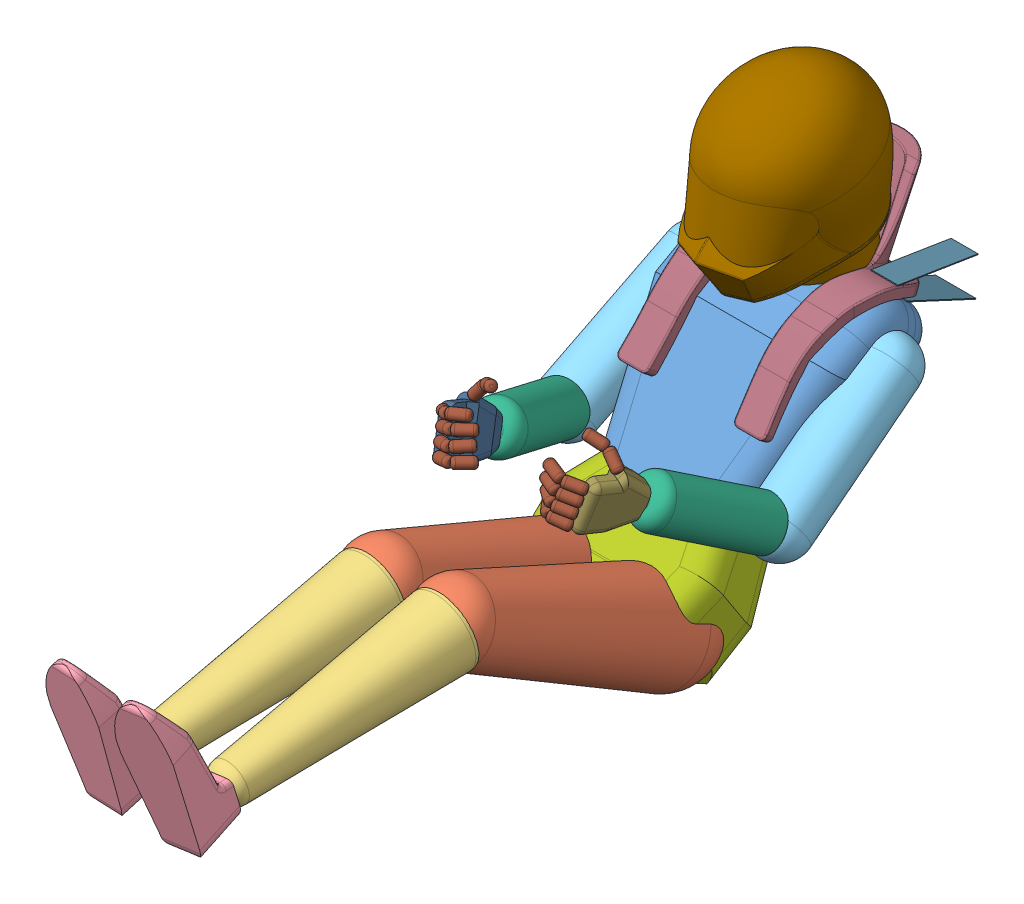
SolidWorks assembly Driver, configuration Default. Lengths in mm.
Overall size (561.73 872.52 1538.68).
40 component instances, 14 part files, 28 mates.
Components (placement in the parent):
- Torso-1: Torso [Default] at (0 0 109.134) x (1 0 0) z (0 0.615661 0.788011) size (365.73 385.32 193.18)
- Upper Leg-1: Upper Leg [Default] at (-76.2 -88.1498 244.8728) x (-0.031181 -0.895731 0.443502) z (0.999512 -0.028692 0.012323) size (181.92 574.72 181.92)
- Lower Leg-1: Lower Leg [Default] at (-75.5001 95.9894 616.8233) x (-0.026742 -0.990268 -0.136579) z (0.999512 -0.028692 0.012323) size (141.98 445.01 146.74)
- Foot-1: Foot [Default] at (-26.031 33.7607 1058.3254) x (-0.999512 0.028692 -0.012323) z (-0.023689 -0.953831 -0.299409) size (130.33 89.92 298.96)
- Upper Arm-1: Upper Arm [Default] at (-203.2 82.3059 139.7838) x (-0.734501 -0.529681 -0.424201) z (0.673249 -0.647184 -0.357615) size (101.6 397.72 101.6)
- Lower Arm-1: Lower Arm [Default] at (-131.2084 188.4007 359.0486) x (-0.836432 0.547989 0.009474) z (-0.283431 -0.417696 -0.863248) size (88.98 88.98 254)
- Upper Leg-2: Upper Leg [Default] at (76.2 -88.1498 244.8728) x (0.999378 0.012809 0.032851) z (0.003362 0.892829 -0.450382) size (181.92 574.72 181.92)
- Lower Leg-2: Lower Leg [Default] at (61.6326 98.7046 615.1809) x (0.999378 0.012809 0.032851) z (-0.017528 0.988884 0.14765) size (141.98 445.01 146.74)
- Upper Arm-3: Upper Arm [Default] at (203.2 90.5447 144.9989) x (0.550591 -0.68786 -0.472968) z (0.830425 0.509095 0.226312) size (101.6 397.72 101.6)
- Lower Arm-2: Lower Arm [Default] at (153.5956 217.6679 359.2302) x (0.197734 0.862423 -0.465971) z (0.195293 -0.500485 -0.843431) size (88.98 88.98 254)
- ass 2-1: ass 2 [Default] at (0 -125.267 302.0282) x (1 0 0) z (0 0.544639 -0.838671) size (327.93 194.64 237.23)
- neck-1: neck [Default] at (0 318.5276 -109.0294) x (1 0 0) z (0 -0.034899 0.999391) size (139.7 241.3 139.7)
- head_helmet-1: head_helmet [Default] at (-0.0708 394.2262 -107.0569) x (0.003968 0.252405 -0.967614) z (0.99999 -0.002944 0.003333) size (346.14 436.25 253.56)
- right_hand-1: right_hand [FU!] at (-108.5097 191.8432 354.8281) x (0.207721 -0.90009 0.383001) z (-0.10626 -0.409987 -0.90588) size (132.83 85.64 143.76)
  - right_palm-1: right_palm [Default] at origin size (98.25 47.38 101.6)
  - finger-1: finger [Default] at (-49.3039 24.13 -53.0317) x (0.50335 -0.086462 -0.859746) z (-0.59338 0.688689 -0.416662) size (19.05 38.1 19.05)
  - finger-2: finger [Default] at (-77.8162 -30.2072 -90.8643) x (0.987884 -0.154582 -0.013755) z (-0.098127 -0.690838 0.71632) size (19.05 38.1 19.05)
  - finger-3: finger [Default] at (9.7976 35.56 -101.6) x (0.49206 -0.497036 0.714726) z (0.870545 0.285971 -0.400465) size (19.05 38.1 19.05)
  - finger-4: finger [Default] at (-11.0552 35.56 -101.6) x (-0.596996 -0.425876 0.679872) z (0.798657 -0.395556 0.453522) size (19.05 38.1 19.05)
  - finger-5: finger [Default] at (10.0013 4.3464 -123.4468) x (0.772648 0.223249 0.594285) z (0.608545 -0.527064 -0.593192) size (19.05 38.1 19.05)
  - finger-6: finger [Default] at (-32.7293 35.56 -101.6) x (0.463457 -0.70203 0.540704) z (0.882821 0.313208 -0.35004) size (19.05 38.1 19.05)
  - finger-7: finger [Default] at (-13.9425 4.5567 -123.5561) x (0.286297 -0.469016 -0.835498) z (-0.951062 -0.033307 -0.3072) size (19.05 38.1 19.05)
  - finger-8: finger [Default] at (31.3089 1.786 -119.2312) x (-0.232922 0.635074 0.736497) z (0.966447 0.066829 0.24802) size (19.05 38.1 19.05)
  - finger-9: finger [Default] at (-35.6395 11.1922 -130.7437) x (0.620311 -0.242152 -0.746041) z (-0.779676 -0.08662 -0.620163) size (19.05 38.1 19.05)
  - finger-10: finger [Default] at (31.0529 35.56 -101.6) x (0.609441 -0.363266 0.704713) z (0.792803 0.28676 -0.537803) size (19.05 38.1 19.05)
- left_hand-1: left_hand [FU!] at (131.8172 221.7495 351.886) x (0.247782 0.946 -0.209018) z (0.261085 -0.272965 -0.925918) size (130.8 89.44 144.04)
  - left_palm-1: left_palm [Default] at origin size (101.6 47.38 101.6)
  - finger-1: finger [Default] at (50.8 26.2111 -54.3719) x (0.69442 0.499709 -0.517757) z (-0.549549 -0.096197 -0.829905) size (19.05 38.1 19.05)
  - finger-2: finger [Default] at (73.4963 -34.5954 -87.6301) x (0.990971 0.115985 0.067264) z (0.027695 -0.667924 0.743714) size (19.05 38.1 19.05)
  - finger-3: finger [Default] at (9.7976 35.56 -101.6) x (0.363062 -0.686021 0.630524) z (0.928864 0.213116 -0.302975) size (19.05 38.1 19.05)
  - finger-4: finger [Default] at (-11.0552 35.56 -101.6) x (-0.291301 -0.669979 0.682841) z (0.953506 -0.261003 0.15068) size (19.05 38.1 19.05)
  - finger-5: finger [Default] at (6.9983 9.055 -128.826) x (0.521272 0.003675 0.853382) z (0.853132 -0.026867 -0.521003) size (19.05 38.1 19.05)
  - finger-6: finger [Default] at (-32.7293 35.56 -101.6) x (0.48185 -0.604968 0.633904) z (0.875847 0.310461 -0.369468) size (19.05 38.1 19.05)
  - finger-7: finger [Default] at (-13.9992 9.081 -128.8361) x (0.138413 -0.293729 -0.945814) z (-0.989877 -0.010765 -0.141518) size (19.05 38.1 19.05)
  - finger-8: finger [Default] at (28.0727 8.9831 -128.7366) x (0.183963 -0.101218 0.977708) z (0.981439 0.073735 -0.177031) size (19.05 38.1 19.05)
  - finger-9: finger [Default] at (-33.7471 7.6239 -127.4872) x (0.645236 0.399892 0.650967) z (0.763899 -0.350359 -0.541947) size (19.05 38.1 19.05)
  - finger-10: finger [Default] at (31.0529 35.56 -101.6) x (0.602627 -0.60222 0.523615) z (0.79418 0.388262 -0.467472) size (19.05 38.1 19.05)
- Foot-3: Foot [Default] at (104.3529 35.9422 1049.7777) x (-0.994071 -0.055729 0.093362) z (0.025364 -0.953827 -0.299285) size (130.33 89.92 298.96)
- HANS_Device-1: HANS_Device [Default] at origin size (315.01 260.03 405.05)
- SeatBelts-1: SeatBelts [Default] at origin size (323.29 466.97 646.34)
Mates (geometry in assembly coordinates):
- Coincident4: coincident: point of Upper Leg-1; point of Lower Leg-1
- Coincident5: coincident: point of Lower Leg-1; point of Foot-1
- Parallel1: parallel: plane of ?; unknown of ?
- Parallel2: parallel: plane of assembly; plane of assembly; plane of Upper Leg-1 through (-76.2 -88.1498 244.8728) normal (0.999512 -0.028692 0.012323); plane of Lower Leg-1 through (-75.5001 95.9894 616.8233) normal (0.999512 -0.028692 0.012323)
- Parallel3: parallel: plane of assembly; plane of assembly; plane of Lower Leg-1 through (-75.5001 95.9894 616.8233) normal (0.999512 -0.028692 0.012323); plane of Foot-1 through (-26.031 33.7607 1058.3254) normal (-0.999512 0.028692 -0.012323)
- Coincident9: coincident: point of Upper Arm-1; point of Lower Arm-1
- Parallel4: parallel: unknown of ?; unknown of ?
- Coincident11: coincident: point of Upper Leg-2; point of Lower Leg-2
- Parallel5: parallel: plane of assembly; plane of assembly; plane of Upper Leg-2 through (76.2 -88.1498 244.8728) normal (0.999378 0.012809 0.032851); plane of Lower Leg-2 through (61.6326 98.7046 615.1809) normal (0.999378 0.012809 0.032851)
- Coincident15: coincident: point of Upper Arm-3; point of Lower Arm-2
- Coincident16: coincident: point of Torso-1; point of Upper Arm-1
- Coincident17: coincident: point of Torso-1; point of Upper Arm-3
- Coincident18: coincident: point of Torso-1; point of ass 2-1
- Angle1: planar angle = 2.80998 rad: plane of assembly; plane of assembly; plane of Torso-1 through (0 0 109.134) normal (0 0.615661 0.788011); plane of ass 2-1 through (0 -125.267 302.0282) normal (0 -0.838671 -0.544639)
- Coincident21: coincident: point of Upper Leg-1; point of ass 2-1
- Coincident22: coincident: point of Upper Leg-2; point of ass 2-1
- Coincident25: coincident: plane of assembly; plane of assembly; plane of Torso-1 through (0 0 109.134) normal (1 0 0); plane of neck-1 through (0 318.5276 -109.0294) normal (1 0 0)
- Neck Angle: planar angle = 3.839724 rad: plane of assembly; plane of assembly; plane of Torso-1 through (0 0 109.134) normal (0 0.615661 0.788011); plane of neck-1 through (0 318.5276 -109.0294) normal (0 -0.034899 0.999391)
- Coincident27: coincident: point of Lower Arm-1; point of right_hand-1/right_palm-1
- Coincident28: coincident: line of assembly; line of Torso-1 through (201.5357 0 109.134) axis (-1 0 0); plane of assembly
- LEAN BACK ANGLE: planar angle = 3.804818 rad: plane of assembly through (0 0 0) normal (0 0 1); plane of Torso-1 through (0 0 109.134) normal (0 0.615661 0.788011); plane of assembly
- Coincident30: coincident: plane of assembly through (0 0 0) normal (1 0 0); plane of Torso-1 through (0 0 109.134) normal (1 0 0); plane of assembly
- Coincident31: coincident: point of Lower Arm-1; plane of assembly
- Coincident32: coincident: point of Lower Arm-2; plane of assembly
- Coincident33: coincident: point of Torso-1; point of neck-1
- Coincident34: coincident: point of Lower Leg-2; point of Foot-3
- Distance1: distance = 286.3039 mm: point of left_hand-1/left_palm-1; point of right_hand-1/right_palm-1
- Lock1: lock: unknown of neck-1; unknown of head_helmet-1
